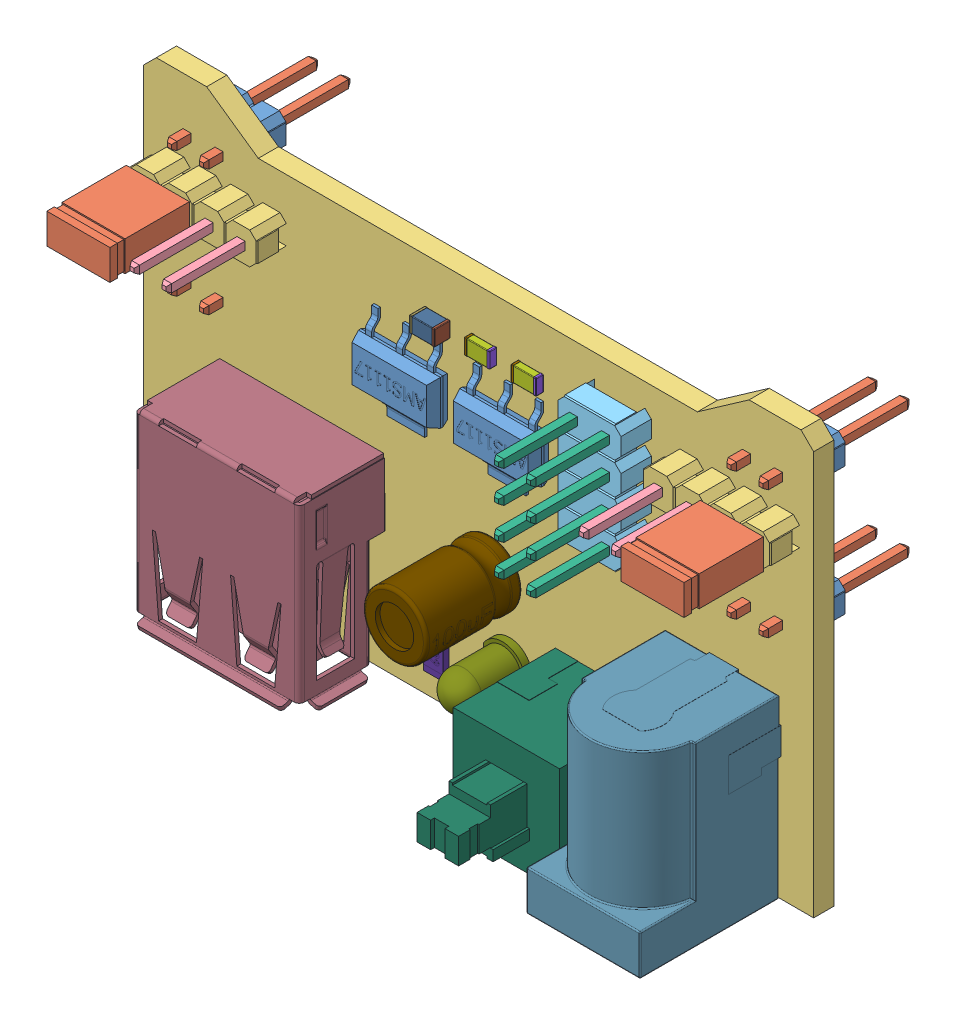
SolidWorks assembly Breadboard_Power_Supply_5V_3.3V, configuration Default. Lengths in mm.
Overall size (53.1 33.04 23.89).
65 component instances, 21 part files, 0 mates.
Components (placement in the parent):
- Breadboard_Power_Supply_5V_3.3V.step-1: Breadboard_Power_Supply_5V_3.3V.step [Default] at origin size (53.1 33.04 23.89)
  - DS1021-1x2S61.step-1: DS1021-1x2S61.step [Default] at (3.435 28.87 0) x (1 0 0) z (0 0 -1) size (5.08 2.54 11.6)
    - body.step-1: body.step [Default] at origin size (5.08 2.54 2.5)
    - pin.step-1: pin.step [Default] at origin size (0.64 0.64 11.6)
    - pin.step-2: pin.step [Default] at (2.54 0 0) size (0.64 0.64 11.6)
  - DS1021-1x2S61_1.step-1: DS1021-1x2S61_1.step [Default] at (47.775 29.03 0) x (1 0 0) z (0 0 -1) size (5.08 2.54 11.6)
    - body.step-1: body.step [Default] at origin size (5.08 2.54 2.5)
    - pin.step-1: pin.step [Default] at origin size (0.64 0.64 11.6)
    - pin.step-2: pin.step [Default] at (2.54 0 0) size (0.64 0.64 11.6)
  - DS1021-1x2S61_2.step-1: DS1021-1x2S61_2.step [Default] at (3.435 18.87 0) x (1 0 0) z (0 0 -1) size (5.08 2.54 11.6)
    - body.step-1: body.step [Default] at origin size (5.08 2.54 2.5)
    - pin.step-1: pin.step [Default] at origin size (0.64 0.64 11.6)
    - pin.step-2: pin.step [Default] at (2.54 0 0) size (0.64 0.64 11.6)
  - DS1021-1x2S61_3.step-1: DS1021-1x2S61_3.step [Default] at (47.775 18.87 0) x (1 0 0) z (0 0 -1) size (5.08 2.54 11.6)
    - body.step-1: body.step [Default] at origin size (5.08 2.54 2.5)
    - pin.step-1: pin.step [Default] at origin size (0.64 0.64 11.6)
    - pin.step-2: pin.step [Default] at (2.54 0 0) size (0.64 0.64 11.6)
  - DS1021-1x4S61.step-1: DS1021-1x4S61.step [Default] at (2.5 26 1.5) size (10.16 2.54 11.6)
    - body_1.step-1: body_1.step [Default] at origin size (10.16 2.54 2.5)
    - pin_1.step-1: pin_1.step [Default] at origin size (0.64 0.64 11.6)
    - pin_1.step-2: pin_1.step [Default] at (2.54 0 0) size (0.64 0.64 11.6)
    - pin_1.step-3: pin_1.step [Default] at (5.08 0 0) size (0.64 0.64 11.6)
    - pin_1.step-4: pin_1.step [Default] at (7.62 0 0) size (0.64 0.64 11.6)
  - DS1021-1x4S61_1.step-1: DS1021-1x4S61_1.step [Default] at (43.182 25.62 1.5) size (10.16 2.54 11.6)
    - body_1.step-1: body_1.step [Default] at origin size (10.16 2.54 2.5)
    - pin_1.step-1: pin_1.step [Default] at origin size (0.64 0.64 11.6)
    - pin_1.step-2: pin_1.step [Default] at (2.54 0 0) size (0.64 0.64 11.6)
    - pin_1.step-3: pin_1.step [Default] at (5.08 0 0) size (0.64 0.64 11.6)
    - pin_1.step-4: pin_1.step [Default] at (7.62 0 0) size (0.64 0.64 11.6)
  - DS1021-2x4S61.step-1: DS1021-2x4S61.step [Default] at (39 19.5 1.5) x (0 1 0) z (0 0 1) size (10.16 5 11.6)
    - body_2.step-1: body_2.step [Default] at origin size (10.16 5 2.5)
    - pin_2.step-1: pin_2.step [Default] at origin size (0.64 0.64 11.6)
    - pin_2.step-2: pin_2.step [Default] at (0 2.54 0) size (0.64 0.64 11.6)
    - pin_2.step-3: pin_2.step [Default] at (2.54 0 0) size (0.64 0.64 11.6)
    - pin_2.step-4: pin_2.step [Default] at (2.54 2.54 0) size (0.64 0.64 11.6)
    - pin_2.step-5: pin_2.step [Default] at (5.08 0 0) size (0.64 0.64 11.6)
    - pin_2.step-6: pin_2.step [Default] at (5.08 2.54 0) size (0.64 0.64 11.6)
    - pin_2.step-7: pin_2.step [Default] at (7.62 0 0) size (0.64 0.64 11.6)
    - pin_2.step-8: pin_2.step [Default] at (7.62 2.54 0) size (0.64 0.64 11.6)
  - C0805_060.step-1: C0805_060.step [Default] at (30.7 26 1.6) size (2 1.25 0.6)
    - C0805_060_1.step-1: C0805_060_1.step [Default] at origin size (2 1.25 0.6)
      - Part 3.step-1: Part 3.step [Default] at origin size (1.8 1.22 0.57)
      - Part 2.step-1: Part 2.step [Default] at origin size (0.2 1.25 0.6)
      - Part 1.step-1: Part 1.step [Default] at origin size (0.2 1.25 0.6)
  - C0805_060.step-2: C0805_060.step [Default] at (27 26 1.6) size (2 1.25 0.6)
    - C0805_060_1.step-1: C0805_060_1.step [Default] at origin size (2 1.25 0.6)
      - Part 3.step-1: Part 3.step [Default] at origin size (1.8 1.22 0.57)
      - Part 2.step-1: Part 2.step [Default] at origin size (0.2 1.25 0.6)
      - Part 1.step-1: Part 1.step [Default] at origin size (0.2 1.25 0.6)
  - C0805_125.step-1: C0805_125.step [Default] at (23.3 26 1.6) size (2 1.25 1.25)
    - C0805_125_1.step-1: C0805_125_1.step [Default] at origin size (2 1.25 1.25)
      - Part 3_1.step-1: Part 3_1.step [Default] at origin size (1.8 1.22 1.22)
      - Part 2_1.step-1: Part 2_1.step [Default] at origin size (0.2 1.25 1.25)
      - Part 1_1.step-1: Part 1_1.step [Default] at origin size (0.2 1.25 1.25)
  - femaleThruHoleUSB.step-1: femaleThruHoleUSB.step [Default] at (12.555 1 5.5) size (15.78 14.44 11.13)
  - DC Jack.step-1: DC Jack.step [Default] at (46 0.0774 7.259) x (1 0 0) z (0 -1 0) size (9.01 14.5 14.01)
  - Toggle Button (8.4 x 8.4 x 13.5mm).step-1: Toggle Button (8.4 x 8.4 x 13.5mm).step [Default] at (37 4.2 1.75) size (8.43 8.48 16.76)
  - LED_3 mm GREEN_shorter legs.step-1: LED_3 mm GREEN_shorter legs.step [Default] at (29 5.432 1.5699) x (1 0 0) z (0 -1 0) size (3.27 8.36 3.54)
  - R22_1206_E24.step-1: R22_1206_E24.step [Default] at (23.4984 3.6291 1.6) x (0 -1 0) z (0 0 1) size (3.1 1.55 0.55)
  - CAPTH100-16.step-1: CAPTH100-16.step [Default] at (27.5004 11.0033 1.6) x (0 -1 0) z (0 0 1) size (5.08 5.09 11.35)
  - AMS1117.step-1: AMS1117.step [Default] at (28.9981 21.2619 1.6) x (-1 0 0) z (0 0 1) size (6.5 7 1.5)
  - AMS1117.step-2: AMS1117.step [Default] at (20.9681 21.2619 1.6) x (-1 0 0) z (0 0 1) size (6.5 7 1.5)
  - Jumper.step-1: Jumper.step [Default] at (6.3221 27.1267 4.3012) x (0 1 0) z (1 0 0) size (2.4 6.3 5)
  - Jumper.step-2: Jumper.step [Default] at (51.8221 26.8767 4.3012) x (0 1 0) z (1 0 0) size (2.4 6.3 5)
  - Breadboard Power Supply.step-1: Breadboard Power Supply.step [Default] at origin size (53.1 33 1.6)
